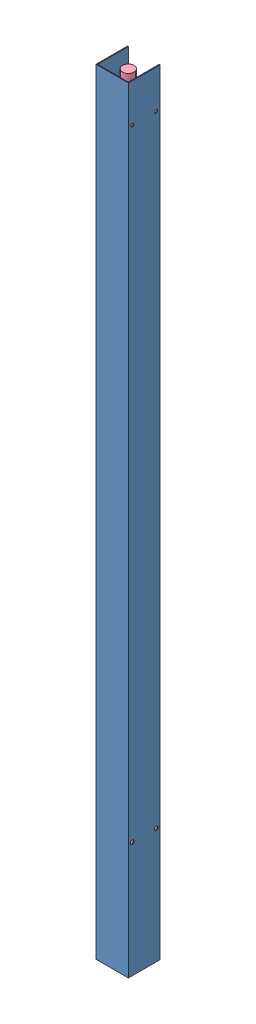
SolidWorks assembly assieme montante, configuration Default. Lengths in mm.
Overall size (42 1005 41).
6 component instances, 4 part files, 12 mates.
Components (placement in the parent):
- montante vite-1: montante vite [Default] at (-247.3746 -737.7267 999.5) x (0 0 -1) z (0 1 0) size (41 42 860)
- supporto cuscinetto-1: supporto cuscinetto [Default] at (-247.3746 223.2733 999.5) x (0 0 -1) z (0 -1 0) size (40 40 12)
- supporto cuscinetto-2: supporto cuscinetto [Default] at (-247.3746 -581.7267 999.5) x (0 0 -1) z (0 -1 0) size (40 40 12)
- cuscinetto-1: cuscinetto [Default] at (-247.3746 223.2733 999.5) x (1 0 0) z (0 0 -1) size (35 11 35)
- cuscinetto-2: cuscinetto [Default] at (-247.3746 -581.7267 999.5) x (1 0 0) z (0 0 -1) size (35 11 35)
- vite tornita-1: vite tornita [Default] at (-247.3746 262.2733 999.5) x (-1 0 0) z (0 -1 0) size (20 20 1000)
Mates (geometry in assembly coordinates):
- Coincidente1: coincident anti-aligned: plane of montante vite-1 through (-227.3746 267.2733 1019.5) normal (-1 0 0); plane of supporto cuscinetto-1 through (-227.3746 211.2733 1019.5) normal (1 0 0)
- Coincidente2: coincident anti-aligned: plane of montante vite-1 through (-267.3746 267.2733 1019.5) normal (0 0 -1); plane of supporto cuscinetto-1 through (-267.3746 211.2733 1019.5) normal (0 0 1)
- Concentrico1: concentric aligned: cylinder of montante vite-1 through (-276.3746 217.2733 984.5) axis (1 0 0) radius 2; cylinder of supporto cuscinetto-1 through (-232.3746 217.2733 984.5) axis (1 0 0) radius 2.5
- Coincidente3: coincident anti-aligned: plane of montante vite-1 through (-267.3746 267.2733 1019.5) normal (1 0 0); plane of supporto cuscinetto-2 through (-267.3746 -593.7267 1019.5) normal (-1 0 0)
- Coincidente4: coincident anti-aligned: plane of montante vite-1 through (-267.3746 267.2733 1019.5) normal (0 0 -1); plane of supporto cuscinetto-2 through (-267.3746 -593.7267 1019.5) normal (0 0 1)
- Concentrico2: concentric anti-aligned: cylinder of montante vite-1 through (-276.3746 -587.7267 984.5) axis (1 0 0) radius 2.5; cylinder of supporto cuscinetto-2 through (-262.3746 -587.7267 984.5) axis (-1 0 0) radius 2.5
- Concentrico7: concentric aligned: cylinder of supporto cuscinetto-1 through (-247.3746 211.2733 999.5) axis (0 1 0) radius 17.5; cylinder of cuscinetto-1 through (-247.3746 212.2733 999.5) axis (0 1 0) radius 17.5
- Coincidente8: coincident aligned: plane of supporto cuscinetto-1 through (-247.3746 223.2733 999.5) normal (0 1 0); plane of cuscinetto-1 through (-247.3746 223.2733 999.5) normal (0 1 0)
- Concentrico8: concentric aligned: cylinder of supporto cuscinetto-2 through (-247.3746 -593.7267 999.5) axis (0 1 0) radius 17.5; cylinder of cuscinetto-2 through (-247.3746 -592.7267 999.5) axis (0 1 0) radius 17.5
- Coincidente9: coincident aligned: plane of supporto cuscinetto-2 through (-247.3746 -581.7267 999.5) normal (0 1 0); plane of cuscinetto-2 through (-247.3746 -581.7267 999.5) normal (0 1 0)
- Coincidente10: coincident anti-aligned: plane of cuscinetto-1 through (-247.3746 212.2733 999.5) normal (0 -1 0); plane of vite tornita-1 through (-247.3746 212.2733 999.5) normal (0 1 0)
- Concentrico9: concentric aligned: cylinder of cuscinetto-1 through (-247.3746 212.2733 999.5) axis (0 1 0) radius 8.5; cylinder of vite tornita-1 through (-247.3746 212.2733 999.5) axis (0 1 0) radius 8.5
